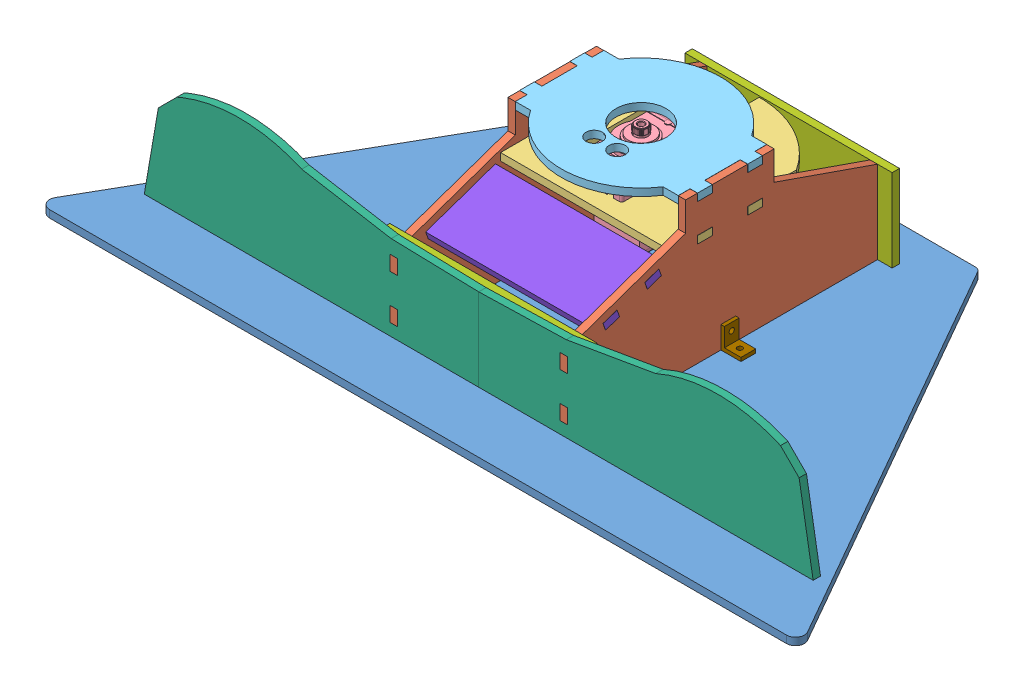
SolidWorks assembly assemblyBaseToBasePlate, configuration Default. Lengths in mm.
Overall size (324.69 66.73 177.8).
13 component instances, 9 part files, 4 mates.
Components (placement in the parent):
- basePlate-1: basePlate [Default] at (8.2817 -31.0943 16.7549) size (324.69 3.17 177.8)
- assemblyRotateBase-1: assemblyRotateBase [Default] at (-18.6609 3.5528 -83.7109) x (-1 0 0) z (0 0 -1) size (287.78 63.55 136.53)
  - rotateBaseSides-1: rotateBaseSides [Default] at (8.1657 0.2779 -4.4977) size (3.18 63.5 136.53)
  - rotateBaseSides-2: rotateBaseSides [Default] at (-65.1133 0.2779 -4.4977) size (3.18 63.5 136.53)
  - rotateBaseServoPlate-1: rotateBaseServoPlate [Default] at (-26.8863 13.0541 -4.4977) size (76.56 3.18 76.2)
  - Standard ServoB-1: Standard ServoB [Default] at (-25.2626 -10.8409 6.7516) x (0 0 -1) z (1 0 0) size (55.73 42.63 19.57)
  - thrustBearingBottom-1: thrustBearingBottom [Default] at (-26.8863 28.9037 -4.4977) size (76.56 3.18 68.58)
  - shoulderFront-1: shoulderFront [Default] at (-26.8355 -31.4721 -74.3477) size (143.94 48.97 3.17)
  - shoulderFront-2: shoulderFront [Default] at (-26.9371 -31.4721 -71.1727) x (-1 0 0) z (0 0 -1) size (143.94 48.97 3.17)
  - chestWall-1: chestWall [Default] at (-26.8355 -13.6921 -71.1727) size (89.15 35.56 3.17)
  - chestWall-2: chestWall [Default] at (-26.8355 -13.6921 59.0023) size (89.15 35.56 3.17)
  - neckCover-1: neckCover [Default] at (-26.8863 4.9145 -46.0534) x (1 0 0) z (0 0.328989 0.944334) size (76.56 3.18 31.75)
- angleBracket_4_40screwThread-1: angleBracket_4_40screwThread [Default] at (50.7378 -27.9193 -78.4951) x (-1 0 0) z (0 1 0) size (8.71 6.35 9.53)
Mates (geometry in assembly coordinates):
- Coincident1: coincident anti-aligned: plane of basePlate-1 through (8.2817 -27.9193 16.7549) normal (0 1 0); plane of assemblyRotateBase-1/rotateBaseSides-2 through (43.2774 -27.9193 -98.2632) normal (0 -1 0)
- Concentric1: concentric aligned: cylinder of basePlate-1 through (51.4617 -31.0943 -78.4951) axis (0 1 0) radius 1.651; cylinder of angleBracket_4_40screwThread-1 through (51.4617 -27.9193 -78.4951) axis (0 1 0) radius 1.1176
- Coincident2: coincident anti-aligned: plane of basePlate-1 through (8.2817 -27.9193 16.7549) normal (0 1 0); plane of angleBracket_4_40screwThread-1 through (46.3817 -27.9193 -75.3201) normal (0 -1 0)
- Concentric3: concentric anti-aligned: cylinder of assemblyRotateBase-1/rotateBaseSides-2 through (43.2774 -21.5693 -78.4951) axis (1 0 0) radius 1.7145; cylinder of angleBracket_4_40screwThread-1 through (55.0939 -21.5693 -78.4951) axis (-1 0 0) radius 1.1176
